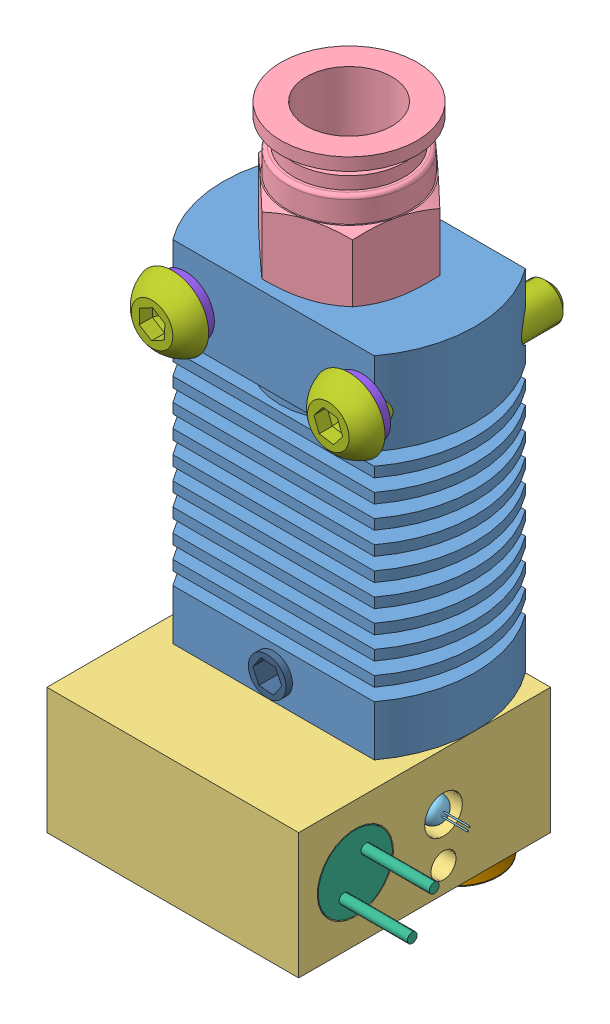
SolidWorks assembly ASM Heating Unit, configuration Standard. Lengths in mm.
Overall size (26.56 56.3 23).
14 component instances, 10 part files, 32 mates.
Components (placement in the parent):
- Radiator-1: Radiator [Standard] x (0 0 1) z (0 -1 0) size (12.27 20 27.8)
- nozzle-1: nozzle [Standard] at (0 -33.8 0) x (0.558876 0 0.829251) z (0 -1 0) size (7.5 6 13)
- Heat block-1: Heat block [Standard] at (0 -33.8 4) x (-1 0 0) z (0 1 0) size (20 20 10)
- Pneumatic joint-1: Pneumatic joint [Standard] at (0 9.5 0) x (0.956349 0 -0.292227) z (0 -1 0) size (11.55 10.8 16.5)
- Nozzle thermistor-1: Nozzle thermistor [Standard] at (8 -28.3 2.5) x (0 0.849837 -0.527046) z (1 0 0) size (2 2 4)
- Heater-1: Heater [Standard] at (10 -28.8 9.5) x (0 0.562925 0.826508) z (-1 0 0) size (5.9 5.9 25.42)
- M3X16 Pan Head Screw-1: M3X16 Pan Head Screw [Standard] at (7 0 8.65) x (0 0 -1) z (0.361928 -0.932206 0) size (18.15 6.02 6.02)
- M3 Split Washer-1: M3 Split Washer [Standard] at (7 0 7) x (-0.704372 0.709831 0) z (-0.709831 -0.704372 0) size (4.59 1 4.6)
- M3×18 Flush Head Screw-1: M3×18 Flush Head Screw [Standard] at (-7 -16.4046 -1.5) x (0 1 0) z (0.170302 0 0.985392) size (18.16 6.72 6.72)
- M3×18 Flush Head Screw-2: M3×18 Flush Head Screw [Standard] at (7 -16.4046 -1.5) x (0 1 0) z (0.992914 0 0.118839) size (18.16 6.72 6.72)
- M3 Screw-1: M3 Screw [Standard] at (0 -33.8 9.5) x (-0.543597 0 -0.839347) z (0.839347 0 -0.543597) size (3 3 3)
- M3X16 Pan Head Screw-2: M3X16 Pan Head Screw [Standard] at (-7 0 8.65) x (0 0 -1) z (0.850683 -0.525679 0) size (18.15 6.02 6.02)
- M3 Split Washer-2: M3 Split Washer [Standard] at (-7 0 7) x (-0.580719 0.814104 0) z (-0.814104 -0.580719 0) size (4.59 1 4.6)
- M3 Screw-2: M3 Screw [Standard] at (0 -21.8 6.5) x (-0.571196 -0.820814 0) z (0.820814 -0.571196 0) size (3 3 3)
Mates (geometry in assembly coordinates):
- Konzentrisch13: concentric aligned: cylinder of Radiator-1 through (0 4 0) axis (0 1 0) radius 4.9; cylinder of Pneumatic joint-1 through (0 -2 0) axis (0 1 0) radius 4.8
- Deckungsgleich11: coincident anti-aligned: plane of Radiator-1 through (0 4 0) normal (0 1 0); plane of Pneumatic joint-1 through (0 4 0) normal (0 -1 0)
- Konzentrisch16: concentric anti-aligned: cylinder of Radiator-1 through (7 -23.8 -1.5) axis (0 -1 0) radius 1.25; cylinder of Heat block-1 through (7 -23.8 -1.5) axis (0 1 0) radius 1.6
- Konzentrisch17: concentric anti-aligned: cylinder of Radiator-1 through (-7 -23.8 -1.5) axis (0 -1 0) radius 1.25; cylinder of Heat block-1 through (-7 -23.8 -1.5) axis (0 1 0) radius 1.6
- Deckungsgleich14: coincident anti-aligned: plane of Radiator-1 through (0 -23.8 0) normal (0 -1 0); plane of Heat block-1 through (0 -23.8 4) normal (0 1 0)
- Deckungsgleich41: coincident anti-aligned: plane of Radiator-1 through (-11.47 -20 6) normal (0 0 1); plane of M3 Split Washer-1 through (7 0 6) normal (0 0 -1)
- Konzentrisch50: concentric aligned: cylinder of Radiator-1 through (7 0 6) axis (0 0 1) radius 1.6; cylinder of M3 Split Washer-1 through (7 0 6) axis (0 0 1) radius 1.55
- Konzentrisch51: concentric aligned: cylinder of Radiator-1 through (7 0 6) axis (0 0 1) radius 1.6; cylinder of M3X16 Pan Head Screw-1 through (7 0 1) axis (0 0 1) radius 1.5
- Deckungsgleich44: coincident anti-aligned: plane of Radiator-1 through (-11.47 -20 6) normal (0 0 1); plane of M3 Split Washer-2 through (-7 0 6) normal (0 0 -1)
- Konzentrisch52: concentric aligned: cylinder of Radiator-1 through (-7 0 6) axis (0 0 1) radius 1.6; cylinder of M3 Split Washer-2 through (-7 0 6) axis (0 0 1) radius 1.55
- Konzentrisch53: concentric aligned: cylinder of Radiator-1 through (-7 0 6) axis (0 0 1) radius 1.6; cylinder of M3X16 Pan Head Screw-2 through (-7 0 1) axis (0 0 1) radius 1.5
- Konzentrisch22: concentric anti-aligned: cylinder of nozzle-1 through (0 -28.8 0) axis (0 -1 0) radius 3; cylinder of Heat block-1 through (0 -23.8 0) axis (0 1 0) radius 3
- Deckungsgleich15: coincident anti-aligned: plane of nozzle-1 through (0 -33.8 0) normal (0 1 0); plane of Heat block-1 through (0 -33.8 4) normal (0 -1 0)
- Deckungsgleich42: coincident anti-aligned: plane of M3X16 Pan Head Screw-1 through (7 0 7) normal (0 0 -1); plane of M3 Split Washer-1 through (7 0 7) normal (0 0 1)
- Konzentrisch14: concentric aligned: cylinder of Heat block-1 through (-10 -28.8 9.5) axis (-1 0 0) radius 3.025; cylinder of Heater-1 through (10 -28.8 9.5) axis (-1 0 0) radius 2.95
- Deckungsgleich12: coincident aligned: plane of Heat block-1 through (-10 -33.8 -6) normal (-1 0 0); plane of Heater-1 through (-10 -28.8 9.5) normal (-1 0 0)
- Konzentrisch15: concentric anti-aligned: cylinder of Heat block-1 through (10 -28.3 2.5) axis (1 0 0) radius 1.5; cylinder of Nozzle thermistor-1 through (10 -28.3 2.5) axis (-1 0 0) radius 1
- Deckungsgleich13: coincident aligned: plane of Heat block-1 through (10 -33.8 14) normal (1 0 0); plane of Nozzle thermistor-1 through (10 -28.3 2.5) normal (1 0 0)
- Konzentrisch18: concentric aligned: cylinder of Heat block-1 through (-7 -23.8 -1.5) axis (0 1 0) radius 1.6; cylinder of M3×18 Flush Head Screw-1 through (-7 -16.4046 -1.5) axis (0 1 0) radius 1.5
- Konzentrisch19: concentric aligned: cone of Heat block-1 through (-7 -33.8 -1.5) axis (0 1 0); cone of M3×18 Flush Head Screw-1 through (-7 -34.3408 -1.5) axis (0 1 0)
- Tangential1: tangent: circle of Heat block-1; cone of M3×18 Flush Head Screw-1 through (-7 -34.3408 -1.5) axis (0 1 0)
- Konzentrisch20: concentric aligned: cylinder of Heat block-1 through (7 -23.8 -1.5) axis (0 1 0) radius 1.6; cylinder of M3×18 Flush Head Screw-2 through (7 -16.4046 -1.5) axis (0 1 0) radius 1.5
- Konzentrisch21: concentric aligned: cylinder of Heat block-1 through (7 -23.8 -1.5) axis (0 1 0) radius 1.6; cone of M3×18 Flush Head Screw-2 through (7 -34.3408 -1.5) axis (0 1 0)
- Tangential2: tangent: circle of Heat block-1; cone of M3×18 Flush Head Screw-2 through (7 -34.3408 -1.5) axis (0 1 0)
- Konzentrisch25: concentric aligned: cylinder of Heat block-1 through (0 -33.8 9.5) axis (0 -1 0) radius 1.5; cylinder of M3 Screw-1 through (0 -30.8 9.5) axis (0 -1 0) radius 1.5
- Deckungsgleich17: coincident aligned: plane of Heat block-1 through (0 -33.8 4) normal (0 -1 0); plane of M3 Screw-1 through (0 -33.8 9.5) normal (0 -1 0)
- Deckungsgleich43: coincident anti-aligned: plane of M3X16 Pan Head Screw-2 through (-7 0 7) normal (0 0 -1); plane of M3 Split Washer-2 through (-7 0 7) normal (0 0 1)
- Deckungsgleich45: coincident anti-aligned: plane of Radiator-1 through (0 0 0) normal (0 -1 0); plane of assembly through (0 0 0) normal (0 1 0)
- Deckungsgleich47: coincident aligned: plane of Radiator-1; plane of assembly through (0 0 0) normal (0 0 1)
- Deckungsgleich48: coincident anti-aligned: plane of Radiator-1; plane of assembly through (0 0 0) normal (1 0 0)
- Konzentrisch54: concentric aligned: cylinder of Radiator-1 through (0 -21.8 6) axis (0 0 1) radius 1.25; cylinder of M3 Screw-2 through (0 -21.8 3.5) axis (0 0 1) radius 1.5
- Abstand1: distance = 0.5 mm aligned: plane of Radiator-1 through (-11.47 -20 6) normal (0 0 1); plane of M3 Screw-2 through (0 -21.8 6.5) normal (0 0 1)
